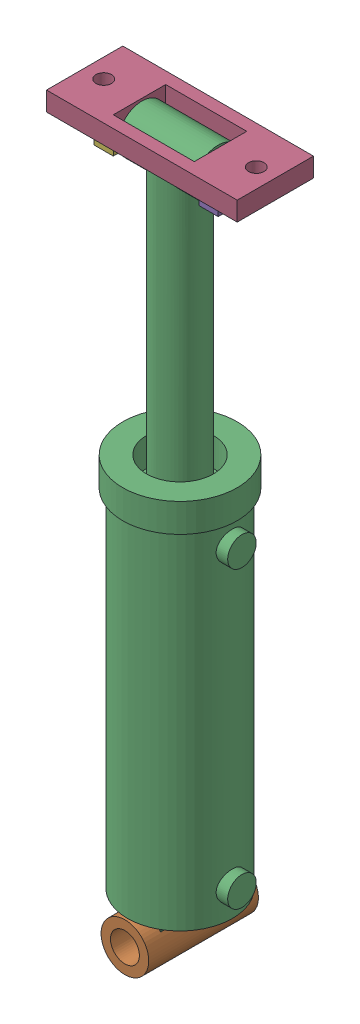
SolidWorks assembly 01-039-00-0, configuration Default. Lengths in mm.
Overall size (254 946.15 152.4).
6 component instances, 5 part files, 0 mates.
Components (placement in the parent):
- hex nut_ai(HNUT 0.7500-10-D-C)-1: hex nut_ai(HNUT 0.7500-10-D-C) [Default] at (-112.7125 840.359 -42.5511) x (1 0 0) z (0 -1 0) size (28.57 33 16.89)
- PMC-21012-1: PMC-21012 [Default] at origin size (158.75 946.15 152.4)
- 01-035-00-0-1: 01-035-00-0 [Default] at (-127 857.25 50.8) size (254 25.4 101.6)
- 01-040-00-0-1: 01-040-00-0 [Default] at (57.15 831.85 -31.75) x (0 0 1) z (-1 0 0) size (63.5 25.4 25.4)
- 01-040-00-0-2: 01-040-00-0 [Default] at (-57.15 831.85 31.75) x (0 0 -1) z (1 0 0) size (63.5 25.4 25.4)
- 01-120-00-0-1: 01-120-00-0 [Default] at (-44.45 850.9 0) x (0 -1 0) z (0 0 1) size (38.1 88.9 38.1)
